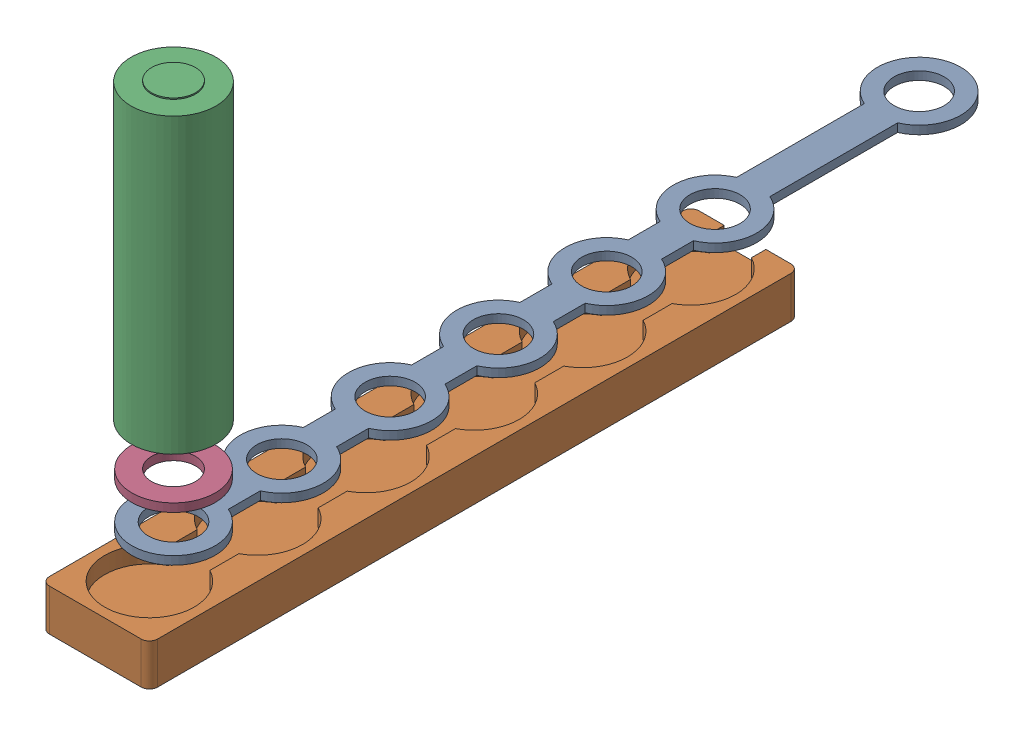
SolidWorks assembly Assem5, configuration Default. Lengths in mm.
Overall size (29.36 116.33 202.76).
4 component instances, 4 part files, 2 mates.
Components (placement in the parent):
- BatteryBusbar_Draft3-1: BatteryBusbar_Draft3 [Default] at (53.1705 78.6793 180.9894) size (20 2 199)
- BatteryCover_Draft6-1: BatteryCover_Draft6 [Default] at (48.1366 64.1523 181.7458) size (26 10 156)
- 20700ACell-1: 20700ACell [Default] at (53.1705 99.8817 180.9894) size (20.35 70.6 20.35)
- PlasticWasher-1: PlasticWasher [Default] at (53.1705 89.6488 180.9894) x (0.989756 0 -0.142771) z (0 -1 0) size (20 20 2)
Mates (geometry in assembly coordinates):
- Concentric1: concentric anti-aligned: circle of 20700ACell-1; circle of PlasticWasher-1
- Concentric3: concentric anti-aligned: circle of BatteryBusbar_Draft3-1; circle of PlasticWasher-1
